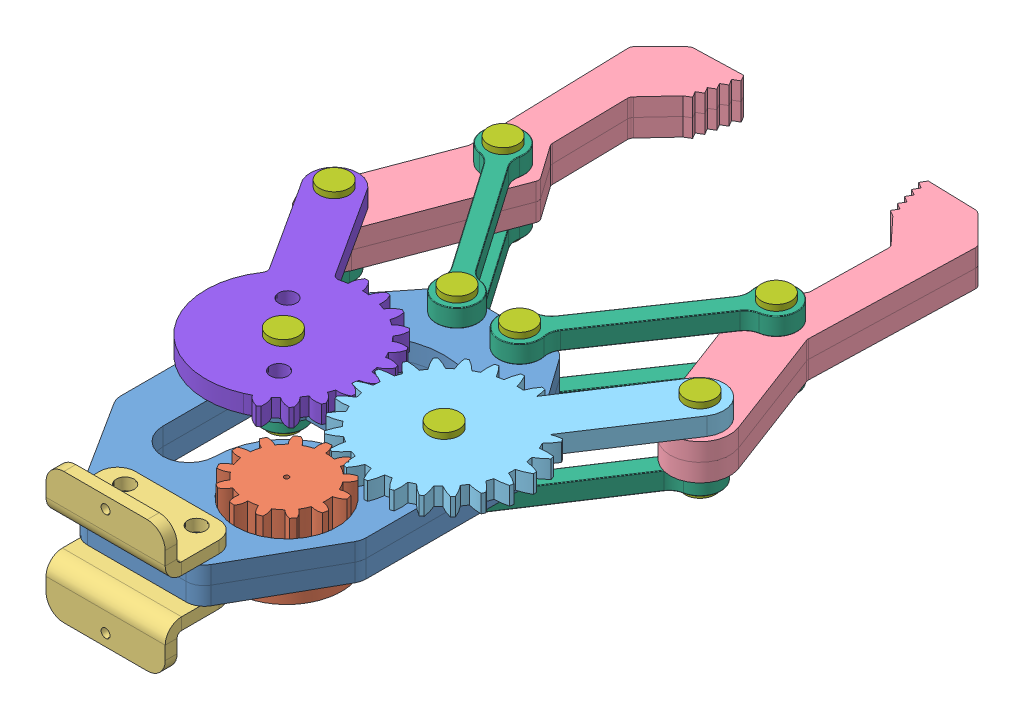
SolidWorks assembly Robot Gripper, configuration Default. Lengths in mm.
Overall size (93.81 22 126.58).
25 component instances, 8 part files, 58 mates.
Components (placement in the parent):
- Base Plate-1: Base Plate [Default] at (28.677 35.3314 42.0504) size (41.21 3 62)
- Base Plate-2: Base Plate [Default] at (28.677 38.3314 42.0504) size (41.21 3 62)
- Base Gear-1: Base Gear [Default] at (36.177 35.3314 55.4504) x (0.640501 0 -0.767958) z (0.767958 0 0.640501) size (18.5 12 18.5)
- Base Mounting Bracket-1: Base Mounting Bracket [Default] at (28.677 41.3314 66.3304) x (0 0 1) z (-1 0 0) size (12 8 20)
- Base Mounting Bracket-2: Base Mounting Bracket [Default] at (28.677 35.3314 66.3304) x (0 0 1) z (1 0 0) size (12 8 20)
- Gripper-1: Gripper [Default] at (-2.0476 38.3314 9.2391) x (0.353427 0 -0.935462) z (0.935462 0 0.353427) size (60.44 3 20.51)
- Gripper-2: Gripper [Default] at (-2.0476 35.3314 9.2391) x (0.353427 0 -0.935462) z (0.935462 0 0.353427) size (60.44 3 20.51)
- Gripper-3: Gripper [Default] at (59.2091 41.3314 9.0985) x (-0.35376 0 -0.935336) z (-0.935336 0 0.35376) size (60.44 3 20.51)
- Gripper-4: Gripper [Default] at (59.2091 38.3314 9.0985) x (-0.35376 0 -0.935336) z (-0.935336 0 0.35376) size (60.44 3 20.51)
- Gear Link 1-1: Gear Link 1 [Default] at (42.177 41.3314 35.0004) x (0.549422 0 -0.835545) z (0.835545 0 0.549422) size (49.16 3 28.33)
- link-1: link [Default] at (5.7278 41.3314 -11.3411) x (0.57094 0 0.820992) z (-0.820992 0 0.57094) size (38 3 7)
- link-2: link [Default] at (5.7278 32.3314 -11.3411) x (0.57094 0 0.820992) z (-0.820992 0 0.57094) size (38 3 7)
- link-4: link [Default] at (51.4263 41.3314 -11.4789) x (-0.564496 0 0.825436) z (-0.825436 0 -0.564496) size (38 3 7)
- pin-1: pin [Default] at (15.177 31.3314 35.0004) x (-0.704787 0 0.709419) z (-0.709419 0 -0.704787) size (5 14 5)
- link-5: link [Default] at (59.2091 32.3314 9.0985) x (-0.549422 0 0.835545) z (-0.835545 0 -0.549422) size (38 3 7)
- link-6: link [Default] at (33.927 32.3314 14.1096) x (0.564496 0 -0.825436) z (0.825436 0 0.564496) size (38 3 7)
- Gear Link 2-3: Gear Link 2 [Default] at (15.177 44.3314 35.0004) x (-0.658476 0 -0.752602) z (-0.752602 0 0.658476) size (49.64 3 27.91)
- pin-2: pin [Default] at (5.7278 31.3314 -11.3411) size (5 14 5)
- pin-3: pin [Default] at (23.427 31.3314 14.1096) size (5 14 5)
- pin-4: pin [Default] at (51.4263 31.3314 -11.4789) size (5 14 5)
- pin-5: pin [Default] at (59.2091 31.3314 9.0985) size (5 14 5)
- pin-6: pin [Default] at (33.927 31.3314 14.1096) size (5 14 5)
- pin-7: pin [Default] at (42.177 31.3314 35.0004) size (5 14 5)
- pin-8: pin [Default] at (-2.0476 31.3314 9.2391) size (5 14 5)
- link-7: link [Default] at (-2.1264 32.3314 9.279) x (0.558173 0 0.829724) z (-0.829724 0 0.558173) size (38 3 7)
Mates (geometry in assembly coordinates):
- Coincident3: coincident: point of Base Plate-1; line of Base Plate-2 through (36.3791 38.3314 11.0504) axis (-1 0 0)
- Coincident4: coincident aligned: line of Base Plate-1 through (7.4656 38.3314 27.2111) axis (0 0 1); line of Base Plate-2 through (7.4656 38.3314 27.2111) axis (0 0 1)
- Coincident8: coincident anti-aligned: plane of Base Plate-2 through (20.8788 41.3314 14.0504) normal (0 1 0); plane of Base Mounting Bracket-1 through (21.677 41.3314 69.3304) normal (0 -1 0)
- Coincident9: coincident aligned: circle of Base Plate-2; circle of Base Mounting Bracket-1
- Coincident10: coincident aligned: circle of Base Plate-2; circle of Base Mounting Bracket-1
- Coincident11: coincident anti-aligned: plane of Base Plate-1 through (20.8788 35.3314 14.0504) normal (0 -1 0); plane of Base Mounting Bracket-2 through (35.677 35.3314 69.3304) normal (0 1 0)
- Coincident12: coincident anti-aligned: circle of Base Plate-1; circle of Base Mounting Bracket-2
- Coincident13: coincident anti-aligned: circle of Base Plate-1; circle of Base Mounting Bracket-2
- Coincident14: coincident anti-aligned: plane of Gripper-3 through (49.1788 38.3314 -18.5326) normal (0 -1 0); plane of Gripper-4 through (49.1788 38.3314 -18.5326) normal (0 1 0)
- Coincident15: coincident aligned: plane of Gripper-3 through (54.5324 38.3314 10.8673) normal (-0.935336 0 0.35376); plane of Gripper-4 through (54.5324 35.3314 10.8673) normal (-0.935336 0 0.35376)
- Concentric2: concentric aligned: cylinder of Gripper-3 through (59.2091 38.3314 9.0985) axis (0 1 0) radius 5; cylinder of Gripper-4 through (59.2091 35.3314 9.0985) axis (0 1 0) radius 5
- Coincident16: coincident aligned: plane of Gripper-1 through (0.2849 41.3314 -11.2945) normal (-0.999584 0 0.028845); plane of Gripper-2 through (0.2849 38.3314 -11.2945) normal (-0.999584 0 0.028845)
- Concentric3: concentric aligned: cylinder of Gripper-1 through (-2.0476 41.3314 9.2391) axis (0 -1 0) radius 5; cylinder of Gripper-2 through (-2.0476 38.3314 9.2391) axis (0 -1 0) radius 5
- Concentric4: concentric aligned: cylinder of Gripper-1 through (5.7278 41.3314 -11.3411) axis (0 -1 0) radius 1.5; cylinder of Gripper-2 through (5.7278 38.3314 -11.3411) axis (0 -1 0) radius 1.5
- Coincident24: coincident anti-aligned: plane of Gripper-1 through (7.9729 38.3314 -18.3956) normal (0 -1 0); plane of Gripper-2 through (7.9729 38.3314 -18.3956) normal (0 1 0)
- Concentric5: concentric aligned: cylinder of Gripper-1 through (5.7278 41.3314 -11.3411) axis (0 -1 0) radius 1.5; cylinder of link-1 through (5.7278 44.3314 -11.3411) axis (0 -1 0) radius 1.5
- Coincident27: coincident anti-aligned: plane of Gripper-1 through (7.9729 41.3314 -18.3956) normal (0 1 0); plane of link-1 through (5.7278 41.3314 -11.3411) normal (0 -1 0)
- Concentric6: concentric aligned: cylinder of Base Plate-2 through (23.427 41.3314 14.1096) axis (0 -1 0) radius 1.5; cylinder of link-1 through (23.427 44.3314 14.1096) axis (0 -1 0) radius 1.5
- Coincident28: coincident anti-aligned: plane of Gripper-2 through (7.9729 35.3314 -18.3956) normal (0 -1 0); plane of link-2 through (5.7278 35.3314 -11.3411) normal (0 1 0)
- Concentric7: concentric aligned: cylinder of Gripper-2 through (5.7278 38.3314 -11.3411) axis (0 -1 0) radius 1.5; cylinder of link-2 through (5.7278 35.3314 -11.3411) axis (0 -1 0) radius 1.5
- Concentric8: concentric aligned: cylinder of Base Plate-1 through (23.427 38.3314 14.1096) axis (0 -1 0) radius 1.5; cylinder of link-2 through (23.427 35.3314 14.1096) axis (0 -1 0) radius 1.5
- Concentric24: concentric anti-aligned: cylinder of Gripper-3 through (51.4263 38.3314 -11.4789) axis (0 1 0) radius 1.5; cylinder of link-4 through (51.4263 44.3314 -11.4789) axis (0 -1 0) radius 1.5
- Coincident31: coincident anti-aligned: plane of Gripper-3 through (49.1788 41.3314 -18.5326) normal (0 1 0); plane of link-4 through (51.4263 41.3314 -11.4789) normal (0 -1 0)
- Concentric25: concentric aligned: cylinder of Base Plate-2 through (33.927 41.3314 14.1096) axis (0 -1 0) radius 1.5; cylinder of link-4 through (33.927 44.3314 14.1096) axis (0 -1 0) radius 1.5
- Coincident32: coincident anti-aligned: plane of Gripper-4 through (49.1788 35.3314 -18.5326) normal (0 -1 0); plane of link-5 through (59.2091 35.3314 9.0985) normal (0 1 0)
- Concentric26: concentric anti-aligned: cylinder of Gripper-4 through (59.2091 35.3314 9.0985) axis (0 1 0) radius 1.5; cylinder of link-5 through (59.2091 35.3314 9.0985) axis (0 -1 0) radius 1.5
- Concentric27: concentric aligned: cylinder of Base Plate-1 through (42.177 38.3314 35.0004) axis (0 -1 0) radius 1.5; cylinder of link-5 through (42.177 35.3314 35.0004) axis (0 -1 0) radius 1.5
- Coincident33: coincident anti-aligned: plane of Gripper-4 through (49.1788 35.3314 -18.5326) normal (0 -1 0); plane of link-6 through (33.927 35.3314 14.1096) normal (0 1 0)
- Concentric28: concentric anti-aligned: cylinder of Gripper-4 through (51.4263 35.3314 -11.4789) axis (0 1 0) radius 1.5; cylinder of link-6 through (51.4263 35.3314 -11.4789) axis (0 -1 0) radius 1.5
- Concentric29: concentric aligned: cylinder of Base Plate-1 through (33.927 38.3314 14.1096) axis (0 -1 0) radius 1.5; cylinder of link-6 through (33.927 35.3314 14.1096) axis (0 -1 0) radius 1.5
- Coincident37: coincident anti-aligned: plane of Base Plate-2 through (20.8788 41.3314 14.0504) normal (0 1 0); plane of Gear Link 1-1 through (42.177 41.3314 35.0004) normal (0 -1 0)
- Concentric30: concentric aligned: cylinder of Base Plate-2 through (42.177 41.3314 35.0004) axis (0 -1 0) radius 1.5; cylinder of Gear Link 1-1 through (42.177 44.3314 35.0004) axis (0 -1 0) radius 1.5
- Concentric31: concentric anti-aligned: cylinder of Gripper-3 through (59.2091 38.3314 9.0985) axis (0 1 0) radius 1.5; cylinder of Gear Link 1-1 through (59.2091 44.3314 9.0985) axis (0 -1 0) radius 1.5
- Coincident38: coincident anti-aligned: plane of Gripper-3 through (49.1788 41.3314 -18.5326) normal (0 1 0); plane of Gear Link 1-1 through (42.177 41.3314 35.0004) normal (0 -1 0)
- Concentric32: concentric anti-aligned: circle of Base Plate-1; circle of Base Gear-1
- Coincident39: coincident anti-aligned: plane of Base Plate-1 through (20.8788 35.3314 14.0504) normal (0 -1 0); plane of Base Gear-1 through (36.177 35.3314 55.4504) normal (0 1 0)
- Coincident40: coincident anti-aligned: plane of Base Plate-2 through (20.8788 41.3314 14.0504) normal (0 1 0); plane of Gear Link 2-3 through (-5.8609 41.3314 12.473) normal (0 -1 0)
- Concentric33: concentric anti-aligned: cylinder of Base Plate-2 through (15.177 41.3314 35.0004) axis (0 -1 0) radius 1.5; cylinder of Gear Link 2-3 through (15.177 41.3314 35.0004) axis (0 1 0) radius 1.5
- Concentric34: concentric anti-aligned: cylinder of Gripper-1 through (-2.0476 41.3314 9.2391) axis (0 -1 0) radius 1.5; cylinder of Gear Link 2-3 through (-2.0476 41.3314 9.2391) axis (0 1 0) radius 1.5
- Coincident41: coincident anti-aligned: plane of pin-1 through (15.177 44.3314 35.0004) normal (0 -1 0); plane of Gear Link 2-3 through (-5.8609 44.3314 12.473) normal (0 1 0)
- Concentric35: concentric anti-aligned: cylinder of pin-1 through (15.177 44.3314 35.0004) axis (0 -1 0) radius 1.5; cylinder of Gear Link 2-3 through (15.177 41.3314 35.0004) axis (0 1 0) radius 1.5
- Coincident42: coincident anti-aligned: plane of link-1 through (5.7278 44.3314 -11.3411) normal (0 1 0); plane of pin-2 through (5.7278 44.3314 -11.3411) normal (0 -1 0)
- Concentric36: concentric aligned: cylinder of link-1 through (5.7278 44.3314 -11.3411) axis (0 -1 0) radius 1.5; cylinder of pin-2 through (5.7278 44.3314 -11.3411) axis (0 -1 0) radius 1.5
- Concentric37: concentric aligned: cylinder of link-4 through (51.4263 44.3314 -11.4789) axis (0 -1 0) radius 1.5; cylinder of pin-4 through (51.4263 44.3314 -11.4789) axis (0 -1 0) radius 1.5
- Coincident43: coincident anti-aligned: plane of link-4 through (51.4263 44.3314 -11.4789) normal (0 1 0); plane of pin-4 through (51.4263 44.3314 -11.4789) normal (0 -1 0)
- Concentric38: concentric aligned: cylinder of Gear Link 1-1 through (59.2091 44.3314 9.0985) axis (0 -1 0) radius 1.5; cylinder of pin-5 through (59.2091 44.3314 9.0985) axis (0 -1 0) radius 1.5
- Coincident44: coincident anti-aligned: plane of Gear Link 1-1 through (42.177 44.3314 35.0004) normal (0 1 0); plane of pin-5 through (59.2091 44.3314 9.0985) normal (0 -1 0)
- Coincident45: coincident anti-aligned: plane of link-1 through (5.7278 44.3314 -11.3411) normal (0 1 0); plane of pin-3 through (23.427 44.3314 14.1096) normal (0 -1 0)
- Concentric39: concentric aligned: cylinder of link-1 through (23.427 44.3314 14.1096) axis (0 -1 0) radius 1.5; cylinder of pin-3 through (23.427 44.3314 14.1096) axis (0 -1 0) radius 1.5
- Coincident46: coincident anti-aligned: plane of link-4 through (51.4263 44.3314 -11.4789) normal (0 1 0); plane of pin-6 through (33.927 44.3314 14.1096) normal (0 -1 0)
- Concentric40: concentric aligned: cylinder of link-4 through (33.927 44.3314 14.1096) axis (0 -1 0) radius 1.5; cylinder of pin-6 through (33.927 44.3314 14.1096) axis (0 -1 0) radius 1.5
- Concentric41: concentric aligned: cylinder of Gear Link 1-1 through (42.177 44.3314 35.0004) axis (0 -1 0) radius 1.5; cylinder of pin-7 through (42.177 44.3314 35.0004) axis (0 -1 0) radius 1.5
- Coincident47: coincident anti-aligned: plane of Gear Link 1-1 through (42.177 44.3314 35.0004) normal (0 1 0); plane of pin-7 through (42.177 44.3314 35.0004) normal (0 -1 0)
- Coincident48: coincident anti-aligned: plane of Gripper-2 through (7.9729 35.3314 -18.3956) normal (0 -1 0); plane of link-7 through (-2.1264 35.3314 9.279) normal (0 1 0)
- Concentric42: concentric aligned: cylinder of pin-1 through (15.177 44.3314 35.0004) axis (0 -1 0) radius 1.5; cylinder of link-7 through (15.177 35.3314 35.0004) axis (0 -1 0) radius 1.5
- Concentric43: concentric anti-aligned: cylinder of Gear Link 2-3 through (-2.0476 41.3314 9.2391) axis (0 1 0) radius 1.5; cylinder of pin-8 through (-2.0476 44.3314 9.2391) axis (0 -1 0) radius 1.5
- Coincident49: coincident anti-aligned: plane of Base Plate-1 through (20.8788 35.3314 14.0504) normal (0 -1 0); plane of link-7 through (-2.1264 35.3314 9.279) normal (0 1 0)
- Coincident50: coincident anti-aligned: plane of Gear Link 2-3 through (-5.8609 44.3314 12.473) normal (0 1 0); plane of pin-8 through (-2.0476 44.3314 9.2391) normal (0 -1 0)
